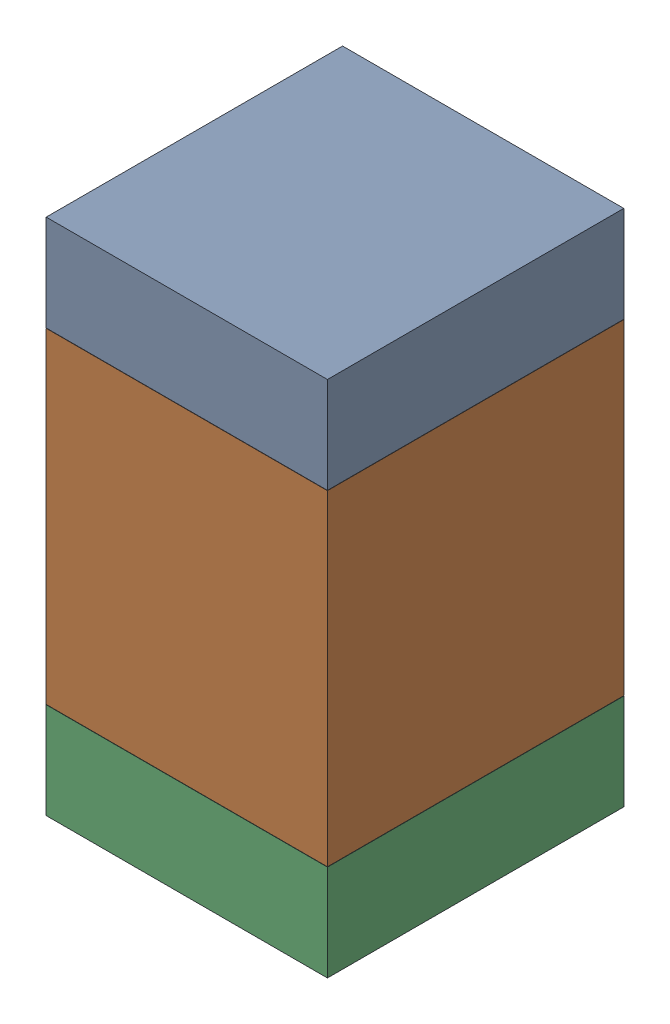
SolidWorks assembly C4, configuration Default. Lengths in mm.
Overall size (0.95 1.75 1).
6 component instances, 2 part files, 0 mates.
Components (placement in the parent):
- 6575495072-1: 6575495072 [Default] at (35.306 21.4135 0) size (0.95 0.32 1)
  - Extruded_6-1: Extruded_6 [Default] at origin size (0.95 0.32 1)
- 6575494912-1: 6575494912 [Default] at (35.306 20.701 0) size (0.95 1.1 1)
  - Extruded_7-1: Extruded_7 [Default] at origin size (0.95 1.1 1)
- 6575495072-2: 6575495072 [Default] at (35.306 19.9885 0) size (0.95 0.32 1)
  - Extruded_6-1: Extruded_6 [Default] at origin size (0.95 0.32 1)
